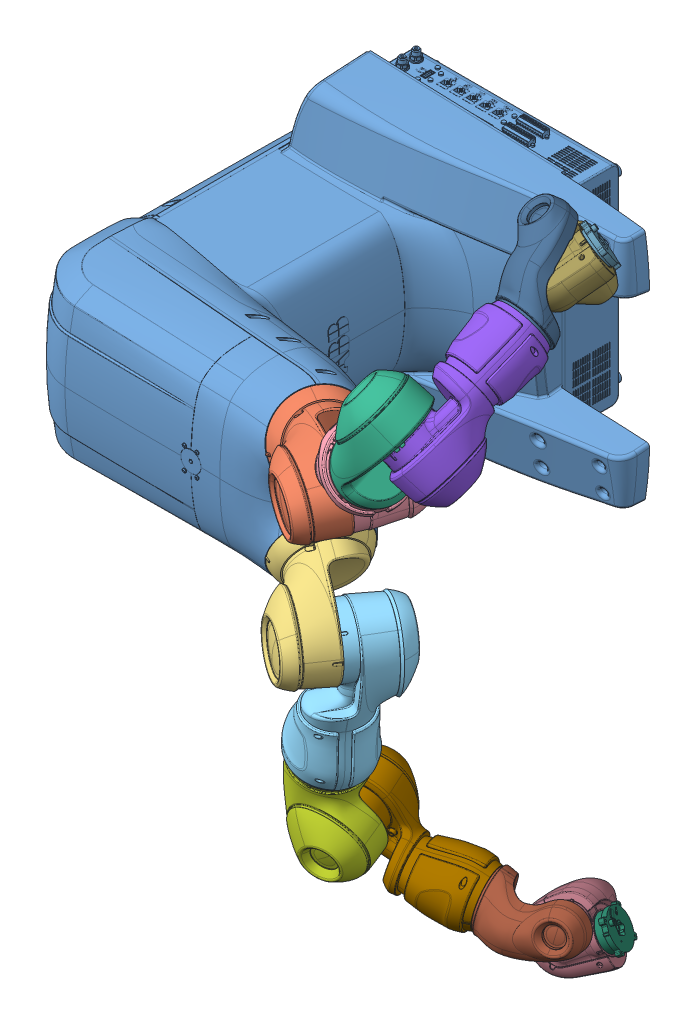
SolidWorks assembly YuMi, configuration 默认. Lengths in mm.
Overall size (859.86 1098.31 750.65).
15 component instances, 15 part files, 28 mates.
Components (placement in the parent):
- IRB14000_rev00_BASE-1: IRB14000_rev00_BASE [默认] at (78.3029 185.4262 387.9425) size (498.03 400.1 575.89)
- IRB14000_rev00_Link1_L-1: IRB14000_rev00_Link1_L [默认] at (-276.2545 365.237 864.6973) x (0.41348 0.801119 0.432716) z (0.895324 -0.27129 -0.353265) size (183.55 197.19 170.45)
- IRB14000_rev00_Link1_R-1: IRB14000_rev00_Link1_R [默认] at (102.8838 424.0595 512.613) x (0.888757 0.256854 0.379653) z (-0.127769 -0.656606 0.743332) size (188.61 166.72 203.93)
- IRB14000_rev00_Link2_L-1: IRB14000_rev00_Link2_L [默认] at (-287.2562 260.6876 847.9218) x (0.225348 0.910795 0.345935) z (0.943753 -0.115881 -0.30968) size (279.57 170.99 163.99)
- IRB14000_rev00_Link2_R-1: IRB14000_rev00_Link2_R [默认] at (648.6811 291.9597 827.2545) x (0.256871 -0.96563 0.039703) z (-0.931025 -0.236227 0.278189) size (277.06 138.66 197.48)
- IRB14000_rev00_Link3_L-1: IRB14000_rev00_Link3_L [默认] at (-187.6409 363.5075 557.7207) x (0.569073 0.817116 -0.092069) z (0.757472 -0.47735 0.44539) size (227.42 170.33 156.08)
- IRB14000_rev00_Link3_R-1: IRB14000_rev00_Link3_R [默认] at (494.6029 379.9033 623.2702) x (0.233128 -0.875757 -0.42273) z (-0.45176 -0.482486 0.750414) size (224.13 170.33 169.24)
- IRB14000_rev00_Link4_L-1: IRB14000_rev00_Link4_L [默认] at (-208.1405 318.0059 607.3983) x (0.531338 0.824789 -0.193398) z (0.80336 -0.418106 0.424028) size (248.32 172.36 184.2)
- IRB14000_rev00_Link4_R-1: IRB14000_rev00_Link4_R [默认] at (468.935 396.3683 635.1909) x (0.279492 -0.857885 -0.431181) z (-0.43793 -0.513546 0.737894) size (244.56 207.3 152.96)
- IRB14000_rev00_Link5_L-1: IRB14000_rev00_Link5_L [默认] at (-270.2458 552.6234 726.6368) x (0.737712 0.605488 -0.298605) z (0.674271 -0.682909 0.281056) size (114.56 107.98 180.93)
- IRB14000_rev00_Link5_R-1: IRB14000_rev00_Link5_R [默认] at (348.8366 299.204 351.6027) x (0.39161 -0.917311 -0.071986) z (-0.302188 -0.202113 0.931575) size (101.64 181.11 103.54)
- IRB14000_rev00_Link6_L-1: IRB14000_rev00_Link6_L [默认] at (-244.4643 667.246 522.9655) x (0.866729 0.497825 0.030828) z (0.456268 -0.816311 0.354197) size (141.34 135.28 112.77)
- IRB14000_rev00_Link6_R-1: IRB14000_rev00_Link6_R [默认] at (-53.638 178.6707 538.5277) x (0.834381 -0.420881 -0.355904) z (0.094976 -0.526262 0.845002) size (138 115.13 137.04)
- IRB14000_rev00_Link7_L-1: IRB14000_rev00_Link7_L [默认] at (-206.2028 501.2714 422.2416) x (0.73022 0.676967 0.09217) z (0.548376 -0.661215 0.511936) size (55.9 54.56 52.3)
- IRB14000_rev00_Link7_R-1: IRB14000_rev00_Link7_R [默认] at (-20.0953 -138.8677 197.0891) x (0.966554 -0.215799 0.138577) z (-0.149772 -0.036333 0.988053) size (55.99 54.56 53.34)
Mates (geometry in assembly coordinates):
- 同心1: concentric anti-aligned: cylinder of IRB14000_rev00_BASE-1 through (104.9954 246.6445 787.3535) axis (0.813798 0.34202 0.469846) radius 36; cylinder of IRB14000_rev00_Link1_L-1 through (129.4094 256.9051 801.4489) axis (-0.813798 -0.34202 -0.469846) radius 36
- 重合1: coincident aligned: plane of IRB14000_rev00_BASE-1 through (177.9142 199.611 759.1428) normal (-0.813798 -0.34202 -0.469846); plane of IRB14000_rev00_Link1_L-1 through (129.4094 256.9051 801.4489) normal (-0.813798 -0.34202 -0.469846)
- 同心2: concentric aligned: cylinder of IRB14000_rev00_Link1_L-1 through (198.246 258.0757 894.5495) axis (0.464989 0.101747 -0.87945) radius 20; cylinder of IRB14000_rev00_Link2_L-1 through (206.4995 259.8817 878.9393) axis (0.464989 0.101747 -0.87945) radius 20
- 重合2: coincident anti-aligned: plane of IRB14000_rev00_Link1_L-1 through (237.6908 321.9716 879.8728) normal (0.464989 0.101747 -0.87945); plane of IRB14000_rev00_Link2_L-1 through (157.0972 275.0466 831.8319) normal (-0.464989 -0.101747 0.87945)
- 同心3: concentric aligned: cylinder of IRB14000_rev00_Link2_L-1 through (292.1868 355.5869 900.0676) axis (0.709564 0.551227 0.438939) radius 20; cylinder of IRB14000_rev00_Link3_L-1 through (296.9054 359.2525 902.9865) axis (0.709564 0.551227 0.438939) radius 20
- 重合3: coincident anti-aligned: plane of IRB14000_rev00_Link2_L-1 through (359.8655 386.1871 866.1449) normal (0.709564 0.551227 0.438939); plane of IRB14000_rev00_Link3_L-1 through (291.5781 388.7498 973.3161) normal (-0.709564 -0.551227 -0.438939)
- 同心4: concentric anti-aligned: cylinder of IRB14000_rev00_Link3_L-1 through (357.5549 476.2914 935.9076) axis (0.695146 -0.649515 -0.308062) radius 15; cylinder of IRB14000_rev00_Link4_L-1 through (380.4947 454.8574 925.7415) axis (-0.695146 0.649515 0.308062) radius 15
- 重合4: coincident anti-aligned: plane of IRB14000_rev00_Link3_L-1 through (368.754 459.0654 890.3763) normal (0.695146 -0.649515 -0.308062); plane of IRB14000_rev00_Link4_L-1 through (352.6591 415.5852 945.7313) normal (-0.695146 0.649515 0.308062)
- 同心5: concentric anti-aligned: cylinder of IRB14000_rev00_Link4_L-1 through (421.8712 529.6078 825.7977) axis (0.037357 0.460597 -0.886823) radius 15; cylinder of IRB14000_rev00_Link5_L-1 through (423.3655 548.0317 790.3248) axis (-0.037357 -0.460597 0.886823) radius 15
- 重合5: coincident anti-aligned: plane of IRB14000_rev00_Link4_L-1 through (378.3747 522.8894 775.3711) normal (0.037357 0.460597 -0.886823); plane of IRB14000_rev00_Link5_L-1 through (413.5363 595.0229 814.3169) normal (-0.037357 -0.460597 0.886823)
- 同心6: concentric aligned: cylinder of IRB14000_rev00_Link5_L-1 through (384.7 624.919 715.4247) axis (0.368962 -0.831095 -0.416111) radius 15; cylinder of IRB14000_rev00_Link6_L-1 through (386.1758 621.5946 713.7603) axis (0.368962 -0.831095 -0.416111) radius 15
- 重合6: coincident anti-aligned: plane of IRB14000_rev00_Link5_L-1 through (366.9433 588.2553 724.8441) normal (0.368962 -0.831095 -0.416111); plane of IRB14000_rev00_Link6_L-1 through (380.0737 618.8553 675.3696) normal (-0.368962 0.831095 0.416111)
- 同心7: concentric aligned: cylinder of IRB14000_rev00_Link6_L-1 through (419.4056 582.3797 720.6139) axis (0.374166 0.542634 -0.752029) radius 10; cylinder of IRB14000_rev00_Link7_L-1 through (423.8956 588.8913 711.5895) axis (0.374166 0.542634 -0.752029) radius 10
- 重合7: coincident anti-aligned: plane of IRB14000_rev00_Link6_L-1 through (402.5561 604.9519 676.658) normal (0.374166 0.542634 -0.752029); plane of IRB14000_rev00_Link7_L-1 through (431.0783 576.2034 670.1052) normal (-0.374166 -0.542634 0.752029)
- 同心8: concentric anti-aligned: cylinder of IRB14000_rev00_BASE-1 through (104.9954 124.208 787.3535) axis (0.813798 -0.34202 0.469846) radius 36; cylinder of IRB14000_rev00_Link1_R-1 through (129.4094 113.9474 801.4489) axis (-0.813798 0.34202 -0.469846) radius 36
- 重合8: coincident aligned: plane of IRB14000_rev00_BASE-1 through (141.7888 56.6331 738.2857) normal (-0.813798 0.34202 -0.469846); plane of IRB14000_rev00_Link1_R-1 through (129.4094 113.9474 801.4489) normal (-0.813798 0.34202 -0.469846)
- 同心9: concentric aligned: cylinder of IRB14000_rev00_Link1_R-1 through (177.1603 52.2246 886.9925) axis (0.495365 -0.014517 -0.868564) radius 20; cylinder of IRB14000_rev00_Link2_R-1 through (185.9531 51.9669 871.5755) axis (0.495365 -0.014517 -0.868564) radius 20
- 重合9: coincident anti-aligned: plane of IRB14000_rev00_Link1_R-1 through (248.4564 79.7966 883.7311) normal (0.495365 -0.014517 -0.868564); plane of IRB14000_rev00_Link2_R-1 through (249.2051 78.989 884.1716) normal (-0.495365 0.014517 0.868564)
- 同心10: concentric anti-aligned: cylinder of IRB14000_rev00_Link2_R-1 through (186.6268 -73.9112 838.3725) axis (-0.317066 -0.933901 -0.165222) radius 20; cylinder of IRB14000_rev00_Link3_R-1 through (170.7735 -120.6062 830.1114) axis (0.317066 0.933901 0.165222) radius 20
- 重合10: coincident aligned: plane of IRB14000_rev00_Link2_R-1 through (120.779 -97.6558 796.3274) normal (-0.317066 -0.933901 -0.165222); circle of IRB14000_rev00_Link3_R-1
- 同心11: concentric anti-aligned: cylinder of IRB14000_rev00_Link3_R-1 through (194.3233 -215.8437 844.5175) axis (-0.267733 0.255264 -0.929064) radius 15; cylinder of IRB14000_rev00_Link4_R-1 through (185.4881 -207.42 813.8584) axis (0.267733 -0.255264 0.929064) radius 15
- 重合11: coincident anti-aligned: plane of IRB14000_rev00_Link3_R-1 through (220.2482 -194.9945 807.2554) normal (-0.267733 0.255264 -0.929064); plane of IRB14000_rev00_Link4_R-1 through (161.3779 -165.1065 832.4322) normal (0.267733 -0.255264 0.929064)
- 同心12: concentric aligned: cylinder of IRB14000_rev00_Link4_R-1 through (286.8142 -268.1571 756.1311) axis (0.924727 -0.202691 -0.322174) radius 15; cylinder of IRB14000_rev00_Link5_R-1 through (292.6307 -269.432 754.1046) axis (0.924727 -0.202691 -0.322174) radius 15
- 重合12: coincident anti-aligned: plane of IRB14000_rev00_Link4_R-1 through (306.9075 -272.5962 692.4406) normal (0.924727 -0.202691 -0.322174); plane of IRB14000_rev00_Link5_R-1 through (326.4185 -227.8282 720.2775) normal (-0.924727 0.202691 0.322174)
- 同心13: concentric aligned: cylinder of IRB14000_rev00_Link5_R-1 through (436.8626 -261.3709 746.7748) axis (-0.36104 -0.199039 -0.911062) radius 15; cylinder of IRB14000_rev00_Link6_R-1 through (437.5847 -260.9728 748.5969) axis (-0.36104 -0.199039 -0.911062) radius 15
- 重合13: coincident anti-aligned: plane of IRB14000_rev00_Link5_R-1 through (408.8246 -235.1495 730.2048) normal (-0.36104 -0.199039 -0.911062); plane of IRB14000_rev00_Link6_R-1 through (435.2597 -231.6384 718.9619) normal (0.36104 0.199039 0.911062)
- 同心14: concentric aligned: cylinder of IRB14000_rev00_Link6_R-1 through (424.1147 -300.2822 709.8369) axis (0.761752 0.500615 -0.41124) radius 10; cylinder of IRB14000_rev00_Link7_R-1 through (438.588 -290.7705 702.0234) axis (0.761752 0.500615 -0.41124) radius 10
- 重合14: coincident anti-aligned: plane of IRB14000_rev00_Link6_R-1 through (445.1241 -293.1695 662.5766) normal (0.761752 0.500615 -0.41124); plane of IRB14000_rev00_Link7_R-1 through (439.4867 -284.7045 662.4391) normal (-0.761752 -0.500615 0.41124)
